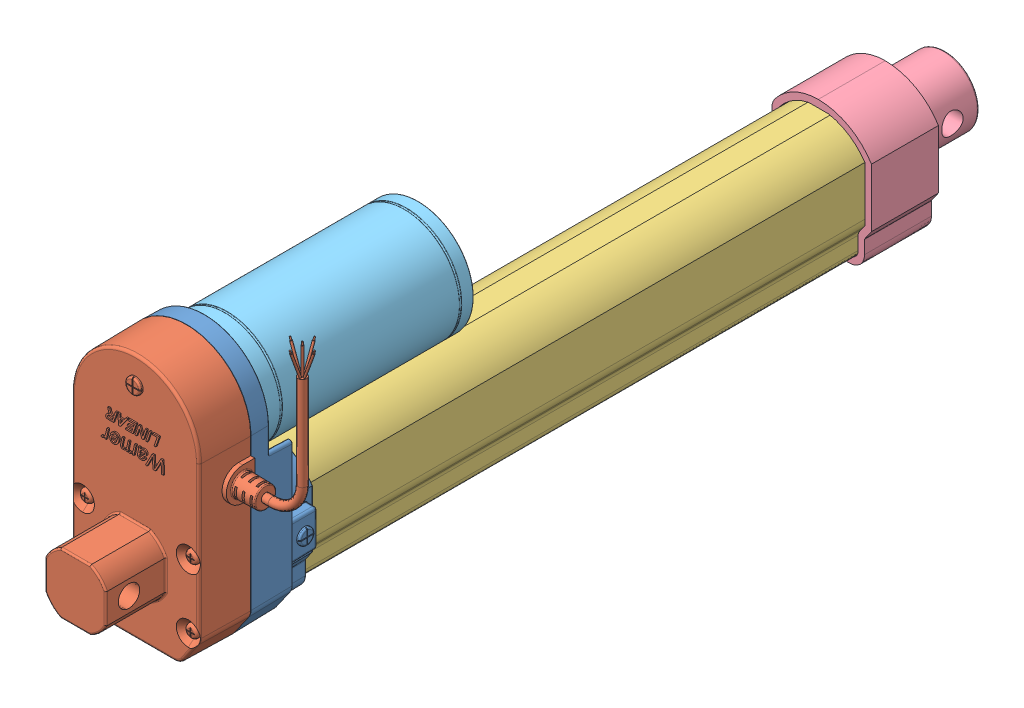
SolidWorks assembly linear actuator, configuration Default. Lengths in mm.
Overall size (61.06 90.36 257.82).
5 component instances, 5 part files, 0 mates.
Components (placement in the parent):
- M-TRACK_BASEPLATE-1: M-TRACK_BASEPLATE [Default] at (0 33.0708 -12.5857) x (0 1 0) z (0 0 1) size (73.8 38.47 30.89)
- M-TRACK_GEARBOX-COVER-1: M-TRACK_GEARBOX-COVER [Default] at (0 33.0708 15.0812) x (0 1 0) z (0 0 -1) size (89.86 61.06 33.04)
- AP4-1: AP4 [Default] at (0 33.0708 -23.4505) x (0 1 0) z (0 0 -1) size (32.99 25.48 181.88)
- M-TRACK_SEAL-1: M-TRACK_SEAL [Default] at (0 33.0708 -194.4688) x (0 1 0) z (0 0 -1) size (37.4 29.52 37.63)
- M-TRACK_CYLINDER-1: M-TRACK_CYLINDER [Default] at origin size (32.77 32.77 65.84)
